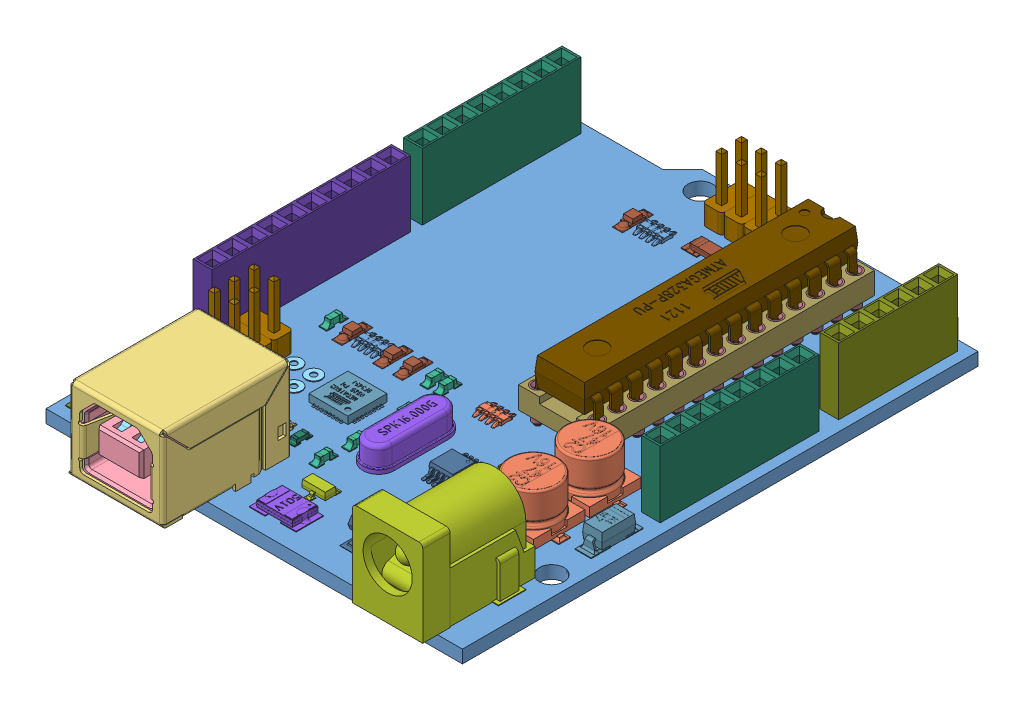
SolidWorks assembly arduino uno, configuration Default. Lengths in mm.
Overall size (53.34 15.25 74.97).
87 component instances, 35 part files, 131 mates.
Components (placement in the parent):
- unoboard blue-1: unoboard blue [Default] at origin size (53.34 1.65 68.58)
- 47uf CAP Dcase-1: 47uf CAP Dcase [Default] at (-9.4141 0 -18.4991) x (0 0 -1) z (1 0 0) size (6.6 5.81 8)
- USB type b-1: USB type b [Default] at (-38.02 0.43 6.35) size (13.72 15.2 16.54)
  - USB SHELL-1: USB SHELL [Default] at origin size (13.72 15.2 16.54)
  - USB core-1: USB core [Default] at origin size (11.3 10.68 15.75)
  - usb top contact-1: usb top contact [Default] at (1.25 6.09 -0.38) size (1 9.67 13.76)
  - usb btm contact-1: usb btm contact [Default] at (1.25 4.41 -0.38) size (1 6.84 11.76)
  - usb btm contact-2: usb btm contact [Default] at (-1.25 4.41 -0.38) size (1 6.84 11.76)
  - usb top contact-2: usb top contact [Default] at (-1.25 6.09 -0.38) size (1 9.67 13.76)
- power jack-1: power jack [Default] at (-7.675 0 1.905) size (11.2 15.2 15.9)
- 47uf CAP Dcase-2: 47uf CAP Dcase [Default] at (-9.4141 0 -25.7132) x (0 0 -1) z (1 0 0) size (6.6 5.81 8)
- crystal-1: crystal [Default] at (-26.162 0 -18.923) x (1 0 0) z (0 0 -1) size (4 5 11)
- 2pin_header__02-1: 2pin_header__02 [Default] at (-46.23 0 -15.75) size (5 11.75 2.54)
- nano - reg-1: nano - reg [Default] at (-17.399 0 -7.747) size (6.5 1.69 8.3)
- led-1: led [Default] at (-34.29 0 -27.94) x (0 0 1) z (-1 0 0) size (4 0.86 1.35)
- 2pin_header__02-2: 2pin_header__02 [Default] at (-30.43 0 -64.91) x (0 0 1) z (-1 0 0) size (5 11.75 2.54)
- dip28-1: dip28 [Default] at (-16.383 1.5 -46.355) x (0 0 -1) z (1 0 0) size (35.48 7.37 10.1)
  - dip28-1: dip28 [Default] at origin size (35.48 2.8 10.1)
  - dip socket pin-1: dip socket pin [Default] at (16.51 2.8 -3.81) size (1.7 7.37 1.7)
  - dip socket pin-2: dip socket pin [Default] at (16.51 2.8 3.81) size (1.7 7.37 1.7)
  - dip socket pin-3: dip socket pin [Default] at (13.97 2.8 -3.81) size (1.7 7.37 1.7)
  - dip socket pin-4: dip socket pin [Default] at (13.97 2.8 3.81) size (1.7 7.37 1.7)
  - dip socket pin-5: dip socket pin [Default] at (11.43 2.8 -3.81) size (1.7 7.37 1.7)
  - dip socket pin-6: dip socket pin [Default] at (11.43 2.8 3.81) size (1.7 7.37 1.7)
  - dip socket pin-7: dip socket pin [Default] at (8.89 2.8 -3.81) size (1.7 7.37 1.7)
  - dip socket pin-8: dip socket pin [Default] at (8.89 2.8 3.81) size (1.7 7.37 1.7)
  - dip socket pin-9: dip socket pin [Default] at (6.35 2.8 -3.81) size (1.7 7.37 1.7)
  - dip socket pin-10: dip socket pin [Default] at (6.35 2.8 3.81) size (1.7 7.37 1.7)
  - dip socket pin-11: dip socket pin [Default] at (3.81 2.8 -3.81) size (1.7 7.37 1.7)
  - dip socket pin-12: dip socket pin [Default] at (3.81 2.8 3.81) size (1.7 7.37 1.7)
  - dip socket pin-13: dip socket pin [Default] at (1.27 2.8 -3.81) size (1.7 7.37 1.7)
  - dip socket pin-14: dip socket pin [Default] at (1.27 2.8 3.81) size (1.7 7.37 1.7)
  - dip socket pin-15: dip socket pin [Default] at (-1.27 2.8 -3.81) size (1.7 7.37 1.7)
  - dip socket pin-16: dip socket pin [Default] at (-1.27 2.8 3.81) size (1.7 7.37 1.7)
  - dip socket pin-17: dip socket pin [Default] at (-3.81 2.8 -3.81) size (1.7 7.37 1.7)
  - dip socket pin-18: dip socket pin [Default] at (-3.81 2.8 3.81) size (1.7 7.37 1.7)
  - dip socket pin-19: dip socket pin [Default] at (-6.35 2.8 -3.81) size (1.7 7.37 1.7)
  - dip socket pin-20: dip socket pin [Default] at (-6.35 2.8 3.81) size (1.7 7.37 1.7)
  - dip socket pin-21: dip socket pin [Default] at (-8.89 2.8 -3.81) size (1.7 7.37 1.7)
  - dip socket pin-22: dip socket pin [Default] at (-8.89 2.8 3.81) size (1.7 7.37 1.7)
  - dip socket pin-23: dip socket pin [Default] at (-11.43 2.8 -3.81) size (1.7 7.37 1.7)
  - dip socket pin-24: dip socket pin [Default] at (-11.43 2.8 3.81) size (1.7 7.37 1.7)
  - dip socket pin-25: dip socket pin [Default] at (-13.97 2.8 -3.81) size (1.7 7.37 1.7)
  - dip socket pin-26: dip socket pin [Default] at (-13.97 2.8 3.81) size (1.7 7.37 1.7)
  - dip socket pin-27: dip socket pin [Default] at (-16.51 2.8 -3.81) size (1.7 7.37 1.7)
  - dip socket pin-28: dip socket pin [Default] at (-16.51 2.8 3.81) size (1.7 7.37 1.7)
- 2pin_header__02-3: 2pin_header__02 [Default] at (-27.89 0 -64.91) x (0 0 1) z (-1 0 0) size (5 11.75 2.54)
- 2pin_header__02-4: 2pin_header__02 [Default] at (-25.35 0 -64.91) x (0 0 1) z (-1 0 0) size (5 11.75 2.54)
- 2pin_header__02-5: 2pin_header__02 [Default] at (-46.23 0 -18.29) size (5 11.75 2.54)
- 2pin_header__02-6: 2pin_header__02 [Default] at (-46.23 0 -20.83) size (5 11.75 2.54)
- atmega16u2-1: atmega16u2 [Default] at (-34.671 0.06 -20) x (1 0 0) z (0 0 -1) size (5.5 1.01 5.5)
- led-2: led [Default] at (-36.83 0 -27.94) x (0 0 1) z (-1 0 0) size (4 0.86 1.35)
- led-3: led [Default] at (-42.037 0 -27.94) x (0 0 1) z (-1 0 0) size (4 0.86 1.35)
- led-4: led [Default] at (-36.576 0 -58.42) x (0 0 1) z (-1 0 0) size (4 0.86 1.35)
- 8 PORT HEADER-3: 8 PORT HEADER [Default] at (-50.8 0 -45.72) x (0 0 -1) z (1 0 0) size (20.32 10.51 2.41)
- 8 PORT HEADER-4: 8 PORT HEADER [Default] at (-2.54 0 -27.94) x (0 0 -1) z (1 0 0) size (20.32 10.51 2.41)
- 6 PORT HEADER-3: 6 PORT HEADER [Default] at (-2.54 0 -50.8) x (0 0 -1) z (1 0 0) size (15.24 10.51 2.41)
- 10 PORT HEADER-1: 10 PORT HEADER [Default] at (-50.8 0 -18.796) x (0 0 -1) z (1 0 0) size (25.4 10.51 2.41)
- ATMEL328P-1: ATMEL328P [Default] at (-16.383 4.3 -46.355) x (0 0 -1) z (1 0 0) size (35 7.27 7.87)
- 102 RESISTOR PACK-1: 102 RESISTOR PACK [Default] at (-33.782 0 -58.42) size (3.2 0.46 3)
- 102 RESISTOR PACK-2: 102 RESISTOR PACK [Default] at (-39.37 0 -27.94) size (3.2 0.46 3)
- 103 RESISTOR PACK-3: 103 RESISTOR PACK [Default] at (-23.876 0 -27.94) size (3.2 0.46 3)
- 220 RESISTOR PACK-1: 220 RESISTOR PACK [Default] at (-36.83 0 -12.827) size (3.2 0.46 3)
- 16mhz crystal - measured-1: 16mhz crystal - measured [Default] at (-24.892 0 -41.275) x (0 0 -1) z (1 0 0) size (3.4 0.8 2)
- PADS001-1: PADS001 [Default] at (-39.878 0.1 -18.288) x (-1 0 0) z (0 0 1) size (4.54 0.1 4.54)
- 603 cap on pad-1: 603 cap on pad [Default] at (-44.45 0 -27.94) x (0 0 -1) z (1 0 0) size (2.76 0.9 1.12)
- ssot3-1: ssot3 [Default] at (-26.5 0 -8.128) x (-1 0 0) z (0 0 -1) size (3 1.13 3.09)
- mf-msmf050-2-1: mf-msmf050-2 [Default] at (-26.5 0 -4.064) size (5.77 1.02 3.72)
- 603 cap on pad-2: 603 cap on pad [Default] at (-29.845 0 -27.94) x (0 0 -1) z (1 0 0) size (2.76 0.9 1.12)
- 603 cap on pad-3: 603 cap on pad [Default] at (-31.496 0 -27.94) x (0 0 -1) z (1 0 0) size (2.76 0.9 1.12)
- lmv358-1: lmv358 [Default] at (-15.24 0 -21.971) x (0 0 -1) z (1 0 0) size (3.7 1.4 2.9)
- 603 cap on pad-4: 603 cap on pad [Default] at (-15.24 0 -18.415) size (2.76 0.9 1.12)
- 603 cap on pad-5: 603 cap on pad [Default] at (-29.845 0 -12.065) x (0 0 1) z (-1 0 0) size (2.76 0.9 1.12)
- 603 cap on pad-6: 603 cap on pad [Default] at (-29.591 0 -22.352) x (0 0 1) z (-1 0 0) size (2.76 0.9 1.12)
- 603 cap on pad-7: 603 cap on pad [Default] at (-29.591 0 -16.002) x (0 0 1) z (-1 0 0) size (2.76 0.9 1.12)
- 603 cap on pad-8: 603 cap on pad [Default] at (-41.91 0 -12.7) x (0 0 1) z (-1 0 0) size (2.76 0.9 1.12)
- lp2985dgkr-1: lp2985dgkr [Default] at (-20.32 0 -19.05) x (0 0 -1) z (1 0 0) size (5.85 1.1 3)
- cd1206 diode-1: cd1206 diode [Default] at (-27.94 0 -59.436) x (0 0 -1) z (1 0 0) size (2.07 0.96 5)
- cd1206 diode-2: cd1206 diode [Default] at (-46.228 0 -13.081) x (0 0 1) z (-1 0 0) size (2.07 0.96 5)
- 603 resistor-1: 603 resistor [Default] at (-29.591 0 -19.05) x (0 0 1) z (-1 0 0) size (2.36 0.61 1.03)
- blm21-1: blm21 [Default] at (-45.085 0 -7.62) x (0 0 -1) z (1 0 0) size (2.76 0.95 1.32)
- m7 diode-1: m7 diode [Default] at (-2.794 0 -21.59) x (0 0 -1) z (1 0 0) size (6.66 2.35 2.5)
- MLC0603-1: MLC0603 [Default] at (-33.655 0 -12.827) x (0 0 -1) z (1 0 0) size (2.36 0.6 1.03)
- MLC0603-2: MLC0603 [Default] at (-39.37 0 -12.827) x (0 0 -1) z (1 0 0) size (2.36 0.6 1.03)
- RESET BUTTON-1: RESET BUTTON [Default] at (-49.403 0 -6.35) size (6.2 3.1 9.6)
  - RESET CORE-1: RESET CORE [Default] at (0 0.1 0) x (-1 0 0) z (0 0 -1) size (6.2 3.1 9.6)
  - RESET-1: RESET [Default] at (0 0.1 0) x (0 0 1) z (-1 0 0) size (7.3 2 6.2)
Mates (geometry in assembly coordinates):
- Distance1: distance = 1.905 mm aligned: plane of power jack-1 through (-7.675 0 1.905) normal (0 0 1); plane of unoboard blue-1 through (0 0 0) normal (0 0 1)
- Coincident2: coincident aligned: plane of unoboard blue-1 through (0 0 0) normal (0 1 0); plane of power jack-1 through (-7.675 0 1.905) normal (0 1 0)
- Coincident3: coincident anti-aligned: plane of unoboard blue-1 through (0 0 0) normal (0 1 0); plane of USB type b-1/USB core-1 through (-38.02 0 6.35) normal (0 -1 0)
- Distance2: distance = 6.35 mm aligned: plane of USB type b-1/USB SHELL-1 through (-38.02 0.43 6.35) normal (0 0 1); plane of unoboard blue-1 through (0 0 0) normal (0 0 1)
- Coincident5: coincident aligned: plane of unoboard blue-1 through (0 0 0) normal (0 1 0); plane of 47uf CAP Dcase-1
- Parallel1: parallel anti-aligned: plane of unoboard blue-1 through (0 0 0) normal (0 0 1); plane of 47uf CAP Dcase-1 through (-9.4141 0 -18.4991) normal (0 0 -1)
- Coincident7: coincident aligned: plane of 47uf CAP Dcase-1 through (-6.1141 1.5 -15.1991) normal (1 0 0); plane of 47uf CAP Dcase-2 through (-6.1141 1.5 -22.4132) normal (1 0 0)
- Coincident8: coincident anti-aligned: plane of unoboard blue-1 through (0 0 0) normal (0 1 0); plane of 47uf CAP Dcase-2 through (-8.1891 0 -25.7132) normal (0 -1 0)
- Distance3: distance = 3.175 mm aligned: plane of power jack-1 through (-3.175 10.5 -1.595) normal (1 0 0); plane of unoboard blue-1 through (0 -1.65 0) normal (1 0 0)
- Distance4: distance = 32 mm aligned: plane of USB type b-1/USB SHELL-1 through (-32 0.43 6.35) normal (1 0 0); plane of unoboard blue-1 through (0 -1.65 0) normal (1 0 0)
- Coincident11: coincident anti-aligned: plane of unoboard blue-1 through (0 0 0) normal (0 1 0); plane of crystal-1 through (-26.162 0 -22.423) normal (0 -1 0)
- Coincident12: coincident anti-aligned: plane of unoboard blue-1 through (0 0 0) normal (0 1 0); plane of 2pin_header__02-1 through (-44.23 0 -14.98) normal (0 -1 0)
- Distance5: distance = 15.75 mm aligned: plane of 2pin_header__02-1 through (-46.23 0 -15.75) normal (0 0 1); plane of assembly through (0 0 0) normal (0 0 1)
- Distance6: distance = 46.23 mm aligned: plane of 2pin_header__02-1 through (-46.23 0 -15.75) normal (1 0 0); plane of assembly through (0 0 0) normal (1 0 0)
- Coincident15: coincident anti-aligned: plane of unoboard blue-1 through (0 0 0) normal (0 1 0); plane of 2pin_header__02-2 through (-31.2 0 -62.91) normal (0 -1 0)
- Distance7: distance = 64.91 mm aligned: plane of 2pin_header__02-2 through (-30.43 0 -64.91) normal (0 0 1); plane of assembly through (0 0 0) normal (0 0 1)
- Distance8: distance = 30.43 mm anti-aligned: plane of 2pin_header__02-2 through (-30.43 0 -64.91) normal (-1 0 0); plane of assembly through (0 0 0) normal (1 0 0)
- Coincident19: coincident anti-aligned: plane of unoboard blue-1 through (0 0 0) normal (0 1 0); plane of nano - reg-1 through (-17.399 0 -7.747) normal (0 -1 0)
- Concentric3: concentric aligned: cylinder of unoboard blue-1 through (-20.193 -10 -62.865) axis (0 1 0) radius 0.4; cylinder of dip28-1/dip socket pin-1 through (-20.193 33.2926 -62.865) axis (0 1 0) radius 0.25
- Concentric4: concentric aligned: cylinder of unoboard blue-1 through (-12.573 -10 -29.845) axis (0 1 0) radius 0.4; cylinder of dip28-1/dip socket pin-28 through (-12.573 33.2926 -29.845) axis (0 1 0) radius 0.25
- Distance9: distance = 1.5 mm anti-aligned: plane of dip28-1/dip28-1 through (-11.333 1.5 -64.095) normal (0 -1 0); plane of unoboard blue-1 through (0 0 0) normal (0 1 0)
- Coincident21: coincident anti-aligned: plane of unoboard blue-1 through (0 0 0) normal (0 1 0); plane of atmega16u2-1 through (-34.671 0 -20) normal (0 -1 0)
- Distance10: distance = 20 mm anti-aligned: plane of atmega16u2-1 through (-34.671 0.06 -20) normal (0 0 -1); plane of unoboard blue-1 through (0 0 0) normal (0 0 1)
- Distance11: distance = 34.671 mm aligned: plane of atmega16u2-1; plane of unoboard blue-1 through (0 0 0) normal (1 0 0)
- Coincident25: coincident anti-aligned: plane of unoboard blue-1 through (0 0 0) normal (0 1 0); plane of led-1 through (-34.29 0 -28.94) normal (0 -1 0)
- Distance12: distance = 34.29 mm anti-aligned: plane of led-1 through (-34.29 0 -27.94) normal (-1 0 0); plane of unoboard blue-1 through (0 0 0) normal (1 0 0)
- Distance13: distance = 27.94 mm aligned: plane of led-1 through (-34.29 0 -27.94) normal (0 0 1); plane of unoboard blue-1 through (0 0 0) normal (0 0 1)
- Coincident28: coincident aligned: plane of led-2 through (-36.83 0 -28.94) normal (0 -1 0); plane of led-3 through (-42.037 0 -28.94) normal (0 -1 0)
- Coincident29: coincident aligned: plane of led-1 through (-34.29 0 -27.94) normal (0 0 1); plane of led-2 through (-36.83 0 -27.94) normal (0 0 1)
- Coincident30: coincident aligned: plane of led-1 through (-34.29 0 -27.94) normal (0 0 1); plane of led-3 through (-42.037 0 -27.94) normal (0 0 1)
- Distance14: distance = 2.54 mm aligned: plane of led-2 through (-36.83 0 -27.94) normal (-1 0 0); plane of led-1 through (-34.29 0 -27.94) normal (-1 0 0)
- Coincident32: coincident anti-aligned: plane of unoboard blue-1 through (0 0 0) normal (0 1 0); plane of led-2 through (-36.83 0 -28.94) normal (0 -1 0)
- Distance15: distance = 42.037 mm anti-aligned: plane of led-3 through (-42.037 0 -27.94) normal (-1 0 0); plane of unoboard blue-1 through (0 0 0) normal (1 0 0)
- Coincident34: coincident anti-aligned: plane of unoboard blue-1 through (0 0 0) normal (0 1 0); plane of led-4 through (-36.576 0 -59.42) normal (0 -1 0)
- Distance16: distance = 36.576 mm anti-aligned: plane of led-4 through (-36.576 0 -58.42) normal (-1 0 0); plane of unoboard blue-1 through (0 0 0) normal (1 0 0)
- Distance17: distance = 58.42 mm aligned: plane of led-4 through (-36.576 0 -58.42) normal (0 0 1); plane of unoboard blue-1 through (0 0 0) normal (0 0 1)
- Coincident37: coincident aligned: plane of unoboard blue-1 through (0 0 0) normal (0 1 0); plane of 8 PORT HEADER-4
- Coincident38: coincident aligned: plane of unoboard blue-1 through (0 0 0) normal (0 1 0); plane of 8 PORT HEADER-3
- Parallel2: parallel aligned: plane of unoboard blue-1 through (0 0 0) normal (1 0 0); plane of 8 PORT HEADER-4 through (-2.54 0 -27.94) normal (1 0 0)
- Parallel3: parallel aligned: plane of unoboard blue-1 through (0 0 0) normal (1 0 0); plane of 8 PORT HEADER-3 through (-50.8 0 -45.72) normal (1 0 0)
- Concentric5: concentric aligned: cylinder of unoboard blue-1 through (-2.54 -1.65 -27.94) axis (0 1 0) radius 0.4; line of 8 PORT HEADER-4 through (-2.54 -2.5255 -27.94) axis (0 1 0)
- Concentric6: concentric aligned: cylinder of unoboard blue-1 through (-50.8 -1.65 -45.72) axis (0 1 0) radius 0.4; line of 8 PORT HEADER-3 through (-50.8 -2.5255 -45.72) axis (0 1 0)
- Coincident43: coincident aligned: plane of unoboard blue-1 through (0 0 0) normal (0 1 0); plane of 10 PORT HEADER-1
- Coincident44: coincident aligned: plane of unoboard blue-1 through (0 0 0) normal (0 1 0); plane of 6 PORT HEADER-3
- Parallel4: parallel aligned: plane of unoboard blue-1 through (0 0 0) normal (1 0 0); plane of 6 PORT HEADER-3 through (-2.54 0 -50.8) normal (1 0 0)
- Parallel5: parallel aligned: plane of unoboard blue-1 through (0 0 0) normal (1 0 0); plane of 10 PORT HEADER-1 through (-50.8 0 -18.796) normal (1 0 0)
- Concentric7: concentric aligned: cylinder of unoboard blue-1 through (-50.8 -1.65 -18.796) axis (0 1 0) radius 0.4; line of 10 PORT HEADER-1 through (-50.8 -2.5255 -18.796) axis (0 1 0)
- Concentric9: concentric aligned: cylinder of unoboard blue-1 through (-2.54 -1.65 -50.8) axis (0 1 0) radius 0.4; line of 6 PORT HEADER-3 through (-2.54 -2.5255 -50.8) axis (0 1 0)
- Coincident50: coincident aligned: plane of dip28-1/dip28-1 through (-16.383 1.5 -46.355) normal (0 0 -1); plane of ATMEL328P-1 through (-16.383 4.3 -46.355) normal (0 0 -1)
- Coincident51: coincident aligned: plane of dip28-1/dip28-1 through (-16.383 1.5 -46.355) normal (1 0 0); plane of ATMEL328P-1 through (-16.383 4.3 -46.355) normal (1 0 0)
- Coincident52: coincident aligned: plane of dip28-1/dip28-1 through (-11.333 4.3 -64.095) normal (0 1 0); plane of ATMEL328P-1
- Distance18: distance = 7.747 mm: plane of nano - reg-1 through (-17.399 0 -7.747) normal (0 0 1); line of unoboard blue-1 through (-53.34 0 0) axis (1 0 0)
- Distance19: distance = 17.399 mm aligned: plane of nano - reg-1 through (-17.399 0 -7.747) normal (1 0 0); plane of unoboard blue-1 through (0 0 0) normal (1 0 0)
- Coincident55: coincident anti-aligned: plane of unoboard blue-1 through (0 0 0) normal (0 1 0); plane of 102 RESISTOR PACK-1 through (-33.982 0 -59.12) normal (0 -1 0)
- Distance20: distance = 33.782 mm aligned: plane of 102 RESISTOR PACK-1 through (-33.782 0 -58.42) normal (1 0 0); plane of unoboard blue-1 through (0 0 0) normal (1 0 0)
- Distance21: distance = 58.42 mm aligned: plane of 102 RESISTOR PACK-1 through (-33.782 0 -58.42) normal (0 0 1); plane of unoboard blue-1 through (0 0 0) normal (0 0 1)
- Coincident58: coincident aligned: plane of 102 RESISTOR PACK-2 through (-39.37 0 -27.94) normal (0 1 0); plane of 103 RESISTOR PACK-3 through (-23.876 0 -27.94) normal (0 1 0)
- Coincident59: coincident aligned: plane of unoboard blue-1 through (0 0 0) normal (0 1 0); plane of 103 RESISTOR PACK-3 through (-23.876 0 -27.94) normal (0 1 0)
- Coincident60: coincident aligned: plane of 102 RESISTOR PACK-2 through (-39.37 0 -27.94) normal (0 0 1); plane of 103 RESISTOR PACK-3 through (-23.876 0 -27.94) normal (0 0 1)
- Distance22: distance = 23.876 mm aligned: plane of 103 RESISTOR PACK-3 through (-23.876 0 -27.94) normal (1 0 0); plane of unoboard blue-1 through (0 0 0) normal (1 0 0)
- Distance23: distance = 39.37 mm aligned: plane of 102 RESISTOR PACK-2 through (-39.37 0 -27.94) normal (1 0 0); plane of unoboard blue-1 through (0 0 0) normal (1 0 0)
- Distance24: distance = 27.94 mm aligned: plane of 102 RESISTOR PACK-2 through (-39.37 0 -27.94) normal (0 0 1); plane of unoboard blue-1 through (0 0 0) normal (0 0 1)
- Distance25: distance = 12.827 mm aligned: plane of 220 RESISTOR PACK-1 through (-36.83 0 -12.827) normal (0 0 1); plane of unoboard blue-1 through (0 0 0) normal (0 0 1)
- Distance26: distance = 36.83 mm aligned: plane of 220 RESISTOR PACK-1 through (-36.83 0 -12.827) normal (1 0 0); plane of unoboard blue-1 through (0 0 0) normal (1 0 0)
- Coincident66: coincident aligned: plane of unoboard blue-1 through (0 0 0) normal (0 1 0); plane of 220 RESISTOR PACK-1 through (-36.83 0 -12.827) normal (0 1 0)
- Coincident67: coincident anti-aligned: plane of unoboard blue-1 through (0 0 0) normal (0 1 0); plane of 16mhz crystal - measured-1 through (-24.892 0 -41.275) normal (0 -1 0)
- Distance27: distance = 41.275 mm anti-aligned: plane of 16mhz crystal - measured-1 through (-24.892 0 -41.275) normal (0 0 -1); plane of unoboard blue-1 through (0 0 0) normal (0 0 1)
- Distance28: distance = 24.892 mm aligned: plane of 16mhz crystal - measured-1 through (-24.892 0 -41.275) normal (1 0 0); plane of unoboard blue-1 through (0 0 0) normal (1 0 0)
- Coincident70: coincident anti-aligned: plane of unoboard blue-1 through (0 0 0) normal (0 1 0); plane of PADS001-1 through (-42.418 0 -18.288) normal (0 -1 0)
- Distance29: distance = 18.288 mm aligned: plane of PADS001-1 through (-39.878 0.1 -18.288) normal (0 0 1); plane of unoboard blue-1 through (0 0 0) normal (0 0 1)
- Distance30: distance = 39.878 mm anti-aligned: plane of PADS001-1; plane of unoboard blue-1 through (0 0 0) normal (1 0 0)
- Distance31: distance = 4.064 mm aligned: plane of mf-msmf050-2-1 through (-26.5 0 -4.064) normal (0 0 1); plane of unoboard blue-1 through (0 0 0) normal (0 0 1)
- Distance32: distance = 26.5 mm aligned: plane of mf-msmf050-2-1 through (-26.5 0 -4.064) normal (1 0 0); plane of unoboard blue-1 through (0 0 0) normal (1 0 0)
- Coincident72: coincident aligned: plane of unoboard blue-1 through (0 0 0) normal (0 1 0); plane of mf-msmf050-2-1 through (-26.5 0 -4.064) normal (0 1 0)
- Distance33: distance = 8.128 mm anti-aligned: plane of unoboard blue-1 through (0 0 0) normal (0 0 1); plane of ssot3-1 through (-26.5 0 -8.128) normal (0 0 -1)
- Coincident74: coincident anti-aligned: plane of ssot3-1 through (-26.5 0 -8.128) normal (-1 0 0); plane of mf-msmf050-2-1 through (-26.5 0 -4.064) normal (1 0 0)
- Coincident75: coincident aligned: plane of unoboard blue-1 through (0 0 0) normal (0 1 0); plane of ssot3-1
- Coincident76: coincident anti-aligned: plane of led-1 through (-34.29 0 -27.94) normal (0 0 1); plane of 603 cap on pad-1 through (-44.45 0 -27.94) normal (0 0 -1)
- Coincident77: coincident aligned: plane of unoboard blue-1 through (0 0 0) normal (0 1 0); plane of 603 cap on pad-1
- Distance34: distance = 44.45 mm aligned: plane of 603 cap on pad-1 through (-44.45 0 -27.94) normal (1 0 0); plane of unoboard blue-1 through (0 0 0) normal (1 0 0)
- Coincident79: coincident aligned: plane of 603 cap on pad-2; plane of 603 cap on pad-3
- Coincident80: coincident aligned: plane of 603 cap on pad-2 through (-29.845 0 -27.94) normal (0 0 -1); plane of 603 cap on pad-3 through (-31.496 0 -27.94) normal (0 0 -1)
- Coincident81: coincident aligned: plane of unoboard blue-1 through (0 0 0) normal (0 1 0); plane of 603 cap on pad-2
- Coincident82: coincident aligned: plane of 603 cap on pad-1 through (-44.45 0 -27.94) normal (0 0 -1); plane of 603 cap on pad-2 through (-29.845 0 -27.94) normal (0 0 -1)
- Distance36: distance = 29.845 mm aligned: plane of 603 cap on pad-2 through (-29.845 0 -27.94) normal (1 0 0); plane of unoboard blue-1 through (0 0 0) normal (1 0 0)
- Distance37: distance = 31.496 mm aligned: plane of 603 cap on pad-3 through (-31.496 0 -27.94) normal (1 0 0); plane of unoboard blue-1 through (0 0 0) normal (1 0 0)
- Distance38: distance = 15.24 mm aligned: plane of unoboard blue-1 through (0 0 0) normal (1 0 0); plane of lmv358-1 through (-15.24 0 -21.971) normal (1 0 0)
- Distance39: distance = 21.971 mm anti-aligned: plane of lmv358-1 through (-15.24 0 -21.971) normal (0 0 -1); plane of unoboard blue-1 through (0 0 0) normal (0 0 1)
- Coincident88: coincident aligned: plane of unoboard blue-1 through (0 0 0) normal (0 1 0); plane of lmv358-1
- Distance40: distance = 18.415 mm aligned: plane of 603 cap on pad-4 through (-15.24 0 -18.415) normal (0 0 1); plane of unoboard blue-1 through (0 0 0) normal (0 0 1)
- Distance41: distance = 15.24 mm aligned: plane of 603 cap on pad-4 through (-15.24 0 -18.415) normal (1 0 0); plane of unoboard blue-1 through (0 0 0) normal (1 0 0)
- Coincident91: coincident aligned: plane of unoboard blue-1 through (0 0 0) normal (0 1 0); plane of 603 cap on pad-4 through (-15.24 0 -18.415) normal (0 1 0)
- Coincident92: coincident aligned: plane of unoboard blue-1 through (0 0 0) normal (0 1 0); plane of 603 cap on pad-7
- Coincident93: coincident aligned: plane of unoboard blue-1 through (0 0 0) normal (0 1 0); plane of 603 cap on pad-6
- Coincident94: coincident aligned: plane of 603 cap on pad-5; plane of unoboard blue-1 through (0 0 0) normal (0 1 0)
- Coincident95: coincident aligned: plane of 603 cap on pad-8; plane of unoboard blue-1 through (0 0 0) normal (0 1 0)
- Coincident96: coincident aligned: plane of 603 cap on pad-7 through (-29.591 0 -16.002) normal (-1 0 0); plane of 603 cap on pad-6 through (-29.591 0 -22.352) normal (-1 0 0)
- Distance42: distance = 29.591 mm anti-aligned: plane of 603 cap on pad-7 through (-29.591 0 -16.002) normal (-1 0 0); plane of unoboard blue-1 through (0 0 0) normal (1 0 0)
- Distance43: distance = 22.352 mm: plane of 603 cap on pad-6 through (-29.591 0 -22.352) normal (0 0 1); line of unoboard blue-1 through (-53.34 0 0) axis (1 0 0)
- Distance44: distance = 16.002 mm aligned: plane of 603 cap on pad-7 through (-29.591 0 -16.002) normal (0 0 1); plane of unoboard blue-1 through (0 0 0) normal (0 0 1)
- Distance45: distance = 29.845 mm anti-aligned: plane of 603 cap on pad-5 through (-29.845 0 -12.065) normal (-1 0 0); plane of unoboard blue-1 through (0 0 0) normal (1 0 0)
- Distance46: distance = 12.065 mm aligned: plane of 603 cap on pad-5 through (-29.845 0 -12.065) normal (0 0 1); plane of unoboard blue-1 through (0 0 0) normal (0 0 1)
- Distance47: distance = 41.91 mm anti-aligned: plane of 603 cap on pad-8 through (-41.91 0 -12.7) normal (-1 0 0); plane of unoboard blue-1 through (0 0 0) normal (1 0 0)
- Distance48: distance = 12.7 mm aligned: plane of 603 cap on pad-8 through (-41.91 0 -12.7) normal (0 0 1); plane of unoboard blue-1 through (0 0 0) normal (0 0 1)
- Distance49: distance = 20.32 mm aligned: plane of lp2985dgkr-1 through (-20.32 0 -19.05) normal (1 0 0); plane of unoboard blue-1 through (0 0 0) normal (1 0 0)
- Distance50: distance = 19.05 mm anti-aligned: plane of lp2985dgkr-1 through (-20.32 0 -19.05) normal (0 0 -1); plane of unoboard blue-1 through (0 0 0) normal (0 0 1)
- Coincident99: coincident aligned: plane of unoboard blue-1 through (0 0 0) normal (0 1 0); plane of lp2985dgkr-1
- Distance51: distance = 27.94 mm aligned: plane of cd1206 diode-1 through (-27.94 0 -59.436) normal (1 0 0); plane of unoboard blue-1 through (0 0 0) normal (1 0 0)
- Distance52: distance = 59.436 mm anti-aligned: plane of cd1206 diode-1 through (-27.94 0 -59.436) normal (0 0 -1); plane of unoboard blue-1 through (0 0 0) normal (0 0 1)
- Coincident102: coincident aligned: plane of unoboard blue-1 through (0 0 0) normal (0 1 0); plane of cd1206 diode-1
- Distance53: distance = 46.228 mm anti-aligned: plane of cd1206 diode-2 through (-46.228 0 -13.081) normal (-1 0 0); plane of unoboard blue-1 through (0 0 0) normal (1 0 0)
- Distance54: distance = 13.081 mm aligned: plane of unoboard blue-1 through (0 0 0) normal (0 0 1); plane of cd1206 diode-2 through (-46.228 0 -13.081) normal (0 0 1)
- Coincident105: coincident aligned: plane of unoboard blue-1 through (0 0 0) normal (0 1 0); plane of cd1206 diode-2
- Distance55: distance = 29.591 mm anti-aligned: plane of 603 resistor-1 through (-29.591 0 -19.05) normal (-1 0 0); plane of unoboard blue-1 through (0 0 0) normal (1 0 0)
- Distance56: distance = 19.05 mm aligned: plane of 603 resistor-1 through (-29.591 0 -19.05) normal (0 0 1); plane of unoboard blue-1 through (0 0 0) normal (0 0 1)
- Coincident108: coincident aligned: plane of unoboard blue-1 through (0 0 0) normal (0 1 0); plane of 603 resistor-1
- Distance57: distance = 7.62 mm anti-aligned: plane of blm21-1 through (-45.085 0 -7.62) normal (0 0 -1); plane of unoboard blue-1 through (0 0 0) normal (0 0 1)
- Distance58: distance = 45.085 mm aligned: plane of blm21-1 through (-45.085 0 -7.62) normal (1 0 0); plane of unoboard blue-1 through (0 0 0) normal (1 0 0)
- Distance59: distance = 21.59 mm anti-aligned: plane of m7 diode-1 through (-2.794 0 -21.59) normal (0 0 -1); plane of unoboard blue-1 through (0 0 0) normal (0 0 1)
- Distance60: distance = 2.794 mm aligned: plane of m7 diode-1 through (-2.794 0 -21.59) normal (1 0 0); plane of unoboard blue-1 through (0 0 0) normal (1 0 0)
- Coincident113: coincident aligned: plane of unoboard blue-1 through (0 0 0) normal (0 1 0); plane of m7 diode-1
- Coincident114: coincident anti-aligned: plane of 220 RESISTOR PACK-1 through (-36.83 0 -12.827) normal (0 0 1); plane of MLC0603-1 through (-33.655 0 -12.827) normal (0 0 -1)
- Distance61: distance = 33.655 mm aligned: plane of MLC0603-1 through (-33.655 0 -12.827) normal (1 0 0); plane of unoboard blue-1 through (0 0 0) normal (1 0 0)
- Coincident115: coincident aligned: plane of unoboard blue-1 through (0 0 0) normal (0 1 0); plane of MLC0603-1
- Coincident116: coincident aligned: plane of unoboard blue-1 through (0 0 0) normal (0 1 0); plane of blm21-1
- Coincident117: coincident anti-aligned: plane of 220 RESISTOR PACK-1 through (-36.83 0 -12.827) normal (0 0 1); plane of MLC0603-2 through (-39.37 0 -12.827) normal (0 0 -1)
- Coincident118: coincident aligned: plane of unoboard blue-1 through (0 0 0) normal (0 1 0); plane of MLC0603-2
- Distance62: distance = 39.37 mm aligned: plane of MLC0603-2 through (-39.37 0 -12.827) normal (1 0 0); plane of unoboard blue-1 through (0 0 0) normal (1 0 0)
- Distance63: distance = 49.403 mm aligned: plane of RESET BUTTON-1 through (-49.403 0 -6.35) normal (1 0 0); plane of unoboard blue-1 through (0 0 0) normal (1 0 0)
- Distance64: distance = 6.35 mm aligned: plane of RESET BUTTON-1; plane of unoboard blue-1 through (0 0 0) normal (0 0 1)
- Coincident122: coincident aligned: plane of unoboard blue-1 through (0 0 0) normal (0 1 0); plane of RESET BUTTON-1 through (-49.403 0 -6.35) normal (0 1 0)
